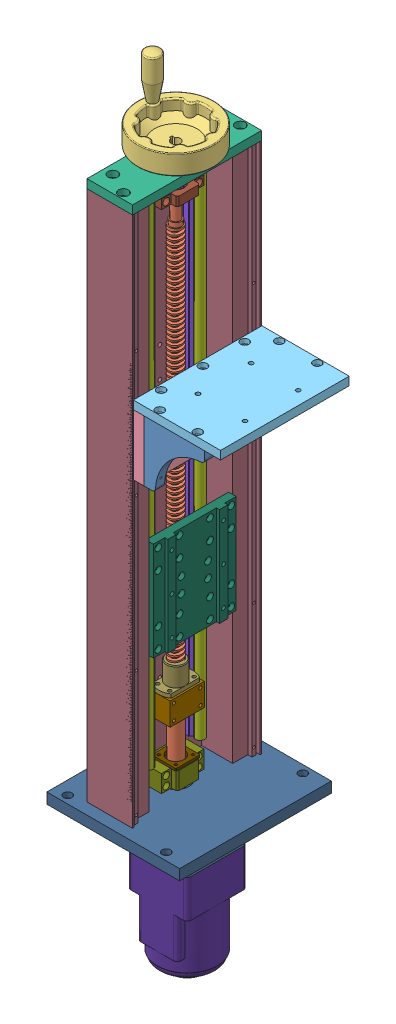
SolidWorks assembly PRODUCT_294513_FDH_GG_ASM_1_ASM, configuration 默认. Lengths in mm.
Overall size (214 1012.5 200).
23 component instances, 18 part files, 13 mates.
Components (placement in the parent):
- ______1-288995_FDH_GG_1-1: ______1-288995_FDH_GG_1 [默认] at (75 478.3351 79) x (0 -1 0) z (0 0 -1) size (80 80 12)
- PRODUCT_159491_FDH_GG_1-1: PRODUCT_159491_FDH_GG_1 [默认] at (32 74 0) x (0 -1 0) z (0.632108 0 0.77488)
- PRODUCT_159996_FDH_GG_1-1: PRODUCT_159996_FDH_GG_1 [默认] at (32 710 0) x (0.236507 0 -0.97163) z (0.97163 0 0.236507) size (100 96.5 102.25)
- _________DEFAULT-289233_FDH_GG_-1: _________DEFAULT-289233_FDH_GG_ [默认] at (75 438.3351 0.25) x (0 0 -1) z (0 1 0) size (169.5 14 80)
- PRODUCT_161183_FDH_GG_1-1: PRODUCT_161183_FDH_GG_1 [默认] at (176 489.3351 0.25) x (0 0 -1) z (1 0 0) size (169.5 11 115)
- ______1-288995_FDH_GG_1-2: ______1-288995_FDH_GG_1 [默认] at (75 478.3351 -78.5) x (0 -1 0) z (0 0 -1) size (80 80 12)
- PRODUCT_160704_FDH_GG_1-1: PRODUCT_160704_FDH_GG_1 [默认] at (32 700 0) x (0 0 -1) z (1 0 0) size (170 11.5 60)
- PRODUCT_160501_FDH_GG_ASM_1_ASM-1: PRODUCT_160501_FDH_GG_ASM_1_ASM [默认] at (30.002 530 34) x (0 0 -1) z (0 -1 0) size (40 25 650)
  - ____2-74989_FDH_GG_1-1: ____2-74989_FDH_GG_1 [默认] at origin size (12 12 650)
  - ____3-75054_FDH_GG_1-1: ____3-75054_FDH_GG_1 [默认] at origin size (40 13.9 650)
- PRODUCT_159736_FDH_GG_1-1: PRODUCT_159736_FDH_GG_1 [默认] at (32 107.5123 0) x (0 0 1) z (0 -1 0) size (45 32 30)
- PRODUCT_295573_FDH_GG_1-1: PRODUCT_295573_FDH_GG_1 [默认] at (57 -14 0) x (0 0 1) z (-1 0 0) size (200 134 199.27)
- PRODUCT_160157_FDH_GG_1-1: PRODUCT_160157_FDH_GG_1 [默认] at (32 674 0) x (0 0 1) z (0 1 0) size (56 38 12)
- _________DEFAULT-289268_FDH_GG_-1: _________DEFAULT-289268_FDH_GG_ [默认] at (32 107.5123 0) x (1 0 0) z (0 1 0) size (25 45 30.31)
- PRODUCT_294687_FDH_GG_1-1: PRODUCT_294687_FDH_GG_1 [默认] at origin size (60 700 170)
- PRODUCT_160927_FDH_GG_1-1: PRODUCT_160927_FDH_GG_1 [默认] at (32 -67 0) x (0 0 -1) z (-1 0 0) size (79 53 79)
- PRODUCT_159238_FDH_GG_1-1: PRODUCT_159238_FDH_GG_1 [默认] at (47 307.51 0) x (0 0 -1) z (0 -1 0) size (109 14 130)
- ______1-289080_FDH_GG_1-1: ______1-289080_FDH_GG_1 [默认] at (32 12.9991 0.0002) x (0 -0.00004 1) z (0 1 0.00004) size (56 38 23)
- PRODUCT_295488_FDH_GG_1-1: PRODUCT_295488_FDH_GG_1 [默认] at (47 -67 0) x (-1 0 0) z (0 -1 0) size (79 79 159)
- PRODUCT_160501_FDH_GG_ASM_1_ASM-2: PRODUCT_160501_FDH_GG_ASM_1_ASM [默认] at (30.002 530 -34) x (0 0 -1) z (0 -1 0) size (40 25 650)
  - ____2-74989_FDH_GG_1-1: ____2-74989_FDH_GG_1 [默认] at origin size (12 12 650)
  - ____3-75054_FDH_GG_1-1: ____3-75054_FDH_GG_1 [默认] at origin size (40 13.9 650)
- PRODUCT_295177_FDH_GG_1-1: PRODUCT_295177_FDH_GG_1 [默认] at (32 27.4991 0.0008) x (-1 0 0) z (0 -1 -0.00004) size (32 32 5)
Mates (geometry in assembly coordinates):
- 重合1: coincident anti-aligned: plane of ______1-288995_FDH_GG_1-1 through (75 478.3351 73) normal (0 1 0); plane of PRODUCT_161183_FDH_GG_1-1 through (61 478.3351 85) normal (0 -1 0)
- 同心1: concentric aligned: cylinder of ______1-288995_FDH_GG_1-1 through (90 478.3351 79) axis (0 1 0) radius 2.5; cylinder of PRODUCT_161183_FDH_GG_1-1 through (90 489.3351 79) axis (0 1 0) radius 3.3
- 同心2: concentric aligned: cylinder of ______1-288995_FDH_GG_1-1 through (140 478.3351 79) axis (0 1 0) radius 2.5; cylinder of PRODUCT_161183_FDH_GG_1-1 through (140 489.3351 79) axis (0 1 0) radius 3.3
- 同心3: concentric aligned: cylinder of PRODUCT_161183_FDH_GG_1-1 through (140 489.3351 -78.5) axis (0 1 0) radius 3.3; cylinder of ______1-288995_FDH_GG_1-2 through (140 478.3351 -78.5) axis (0 1 0) radius 2.5
- 同心4: concentric aligned: cylinder of PRODUCT_161183_FDH_GG_1-1 through (90 489.3351 -78.5) axis (0 1 0) radius 3.3; cylinder of ______1-288995_FDH_GG_1-2 through (90 478.3351 -78.5) axis (0 1 0) radius 2.5
- 重合2: coincident anti-aligned: plane of _________DEFAULT-289233_FDH_GG_-1 through (61 478.3351 -84.5) normal (0 1 0); plane of PRODUCT_161183_FDH_GG_1-1 through (61 478.3351 85) normal (0 -1 0)
- 重合3: coincident aligned: plane of _________DEFAULT-289233_FDH_GG_-1 through (61 478.3351 -84.5) normal (-1 0 0); plane of PRODUCT_161183_FDH_GG_1-1 through (61 478.3351 85) normal (-1 0 0)
- 同心5: concentric aligned: cylinder of _________DEFAULT-289233_FDH_GG_-1 through (68 463.3351 -78.5) axis (-1 0 0) radius 5.5; cylinder of ______1-288995_FDH_GG_1-2 through (75 463.3351 -78.5) axis (-1 0 0) radius 2.5
- 距离1: distance = 30.5 mm aligned: plane of PRODUCT_159238_FDH_GG_1-1 through (57 177.51 54.5) normal (0 0 1); plane of PRODUCT_294687_FDH_GG_1-1 through (0 0 85) normal (0 0 1)
- 距离2: distance = 5 mm aligned: plane of PRODUCT_159238_FDH_GG_1-1 through (57 177.51 54.5) normal (1 0 0); plane of PRODUCT_294687_FDH_GG_1-1 through (52 0 55) normal (1 0 0)
- 重合7: coincident anti-aligned: plane of _________DEFAULT-289233_FDH_GG_-1 through (61 478.3351 -84.5) normal (-1 0 0); plane of PRODUCT_159238_FDH_GG_1-1 through (61 177.51 39.5) normal (1 0 0)
- 平行1: parallel aligned: plane of ______1-288995_FDH_GG_1-1 through (150 468.1563 85) normal (0 0 1); plane of PRODUCT_294687_FDH_GG_1-1 through (0 0 85) normal (0 0 1)
- 重合9: coincident aligned: plane of PRODUCT_161183_FDH_GG_1-1 through (176 478.3351 85) normal (0 0 1); plane of PRODUCT_294687_FDH_GG_1-1 through (0 0 85) normal (0 0 1)
